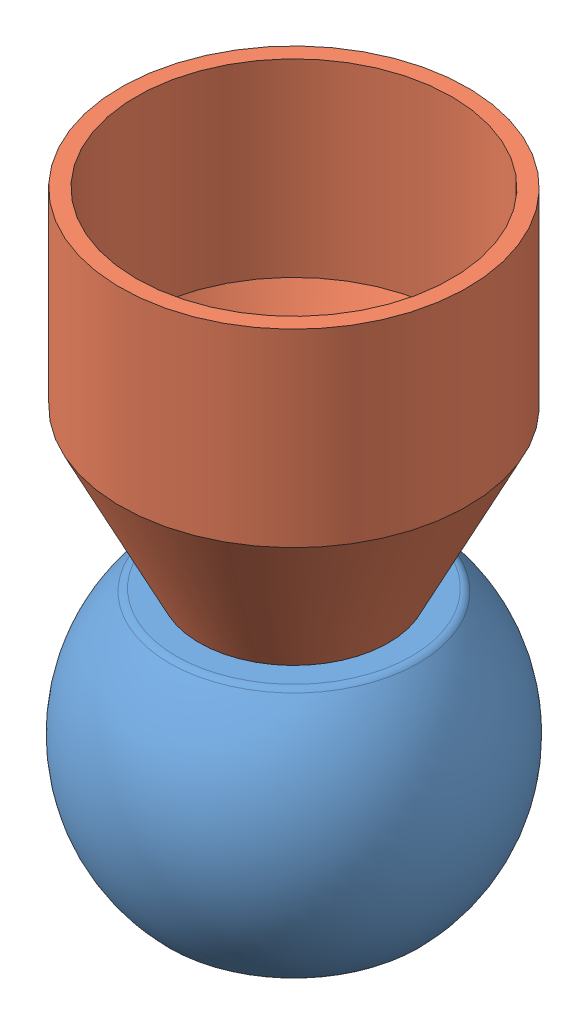
SolidWorks assembly MixShortTruNhua, configuration Default. Lengths in mm.
Overall size (15.13 19 15.13).
2 component instances, 2 part files, 2 mates.
Components (placement in the parent):
- Ball Joint 5x008-1: Ball Joint 5x008 [M22*1.5] at (0.7661 5.3646 10.6063) size (11.11 8 11.11)
- Short Tru Nhua-1: Short Tru Nhua [Default] at (0.7661 20.3646 10.6063) x (-0.852463 0 -0.522787) z (-0.522787 0 0.852463) size (11 11 11)
Mates (geometry in assembly coordinates):
- Concentric1: concentric: circle of Ball Joint 5x008-1; circle of Short Tru Nhua-1
- Coincident1: coincident anti-aligned: plane of Ball Joint 5x008-1 through (4.6207 9.3646 10.6063) normal (0 1 0); plane of Short Tru Nhua-1 through (-1.7913 9.3646 9.0379) normal (0 -1 0)
